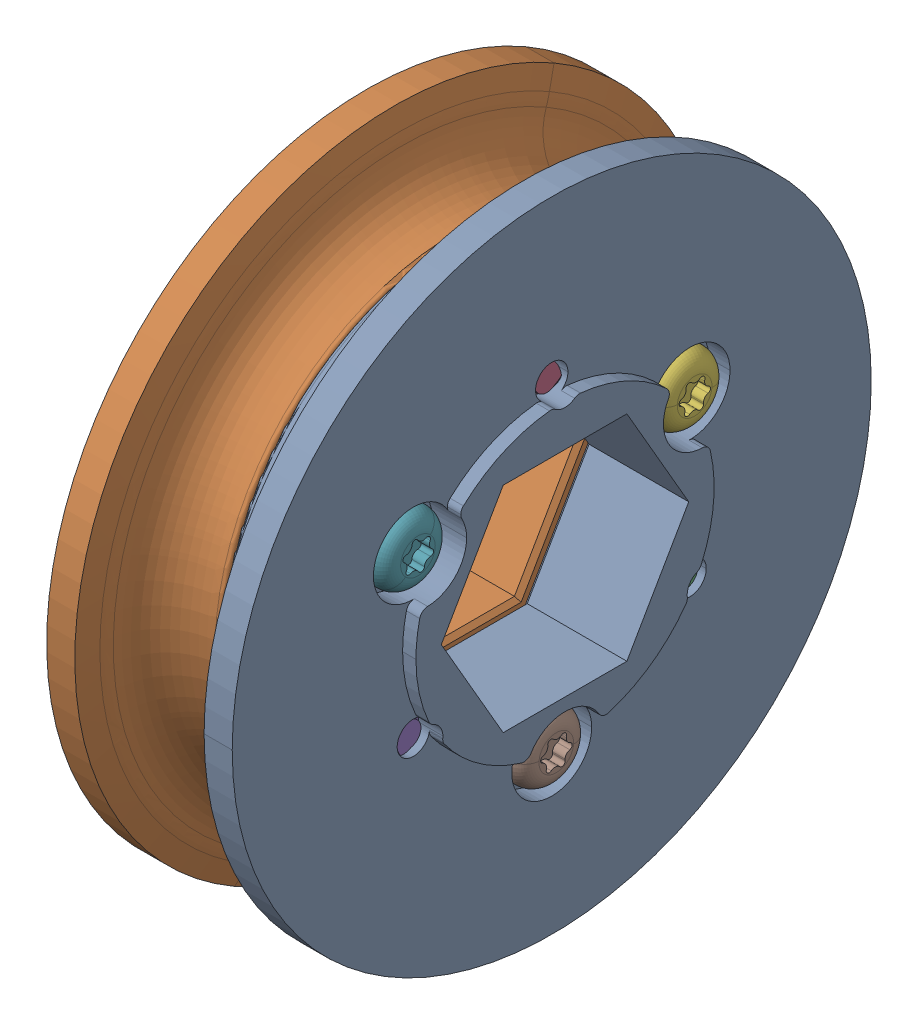
SolidWorks assembly WCP-0096 Rev6-3.step, configuration Default. Lengths in mm.
Overall size (12.65 52.05 52.05).
8 component instances, 2 part files, 0 mates.
Components (placement in the parent):
- WCP-0096-001 Rev6.step-1: WCP-0096-001 Rev6.step [Default] at origin size (7.57 38.1 38.1)
- WCP-0096-001 Rev6.step-2: WCP-0096-001 Rev6.step [Default] x (-1 0 0) z (0 0.866025 -0.5) size (7.57 38.1 38.1)
- WCP-0356 Rev1.step-1: WCP-0356 Rev1.step [Default] at (0.4817 -4.7625 -8.2489) x (0 -0.126969 0.991907) z (0 -0.991907 -0.126969) size (4.06 11.05 4.06)
- WCP-0356 Rev1.step-2: WCP-0356 Rev1.step [Default] at (0.4817 9.525 0) x (0 0.866766 0.498715) z (0 -0.498715 0.866766) size (4.06 11.05 4.06)
- WCP-0356 Rev1.step-3: WCP-0356 Rev1.step [Default] at (0.4817 -4.7625 8.2489) x (0 -0.994015 -0.109248) z (0 0.109248 -0.994015) size (4.06 11.05 4.06)
- WCP-0356 Rev1.step-4: WCP-0356 Rev1.step [Default] at (-0.4817 4.7625 -8.2489) x (0 -0.997555 0.069879) z (0 0.069879 0.997555) size (4.06 11.05 4.06)
- WCP-0356 Rev1.step-5: WCP-0356 Rev1.step [Default] at (-0.4817 4.7625 8.2489) x (0 -0.7202 -0.693767) z (0 -0.693767 0.7202) size (4.06 11.05 4.06)
- WCP-0356 Rev1.step-6: WCP-0356 Rev1.step [Default] at (-0.4817 -9.525 0) x (0 -0.997555 0.069879) z (0 0.069879 0.997555) size (4.06 11.05 4.06)
